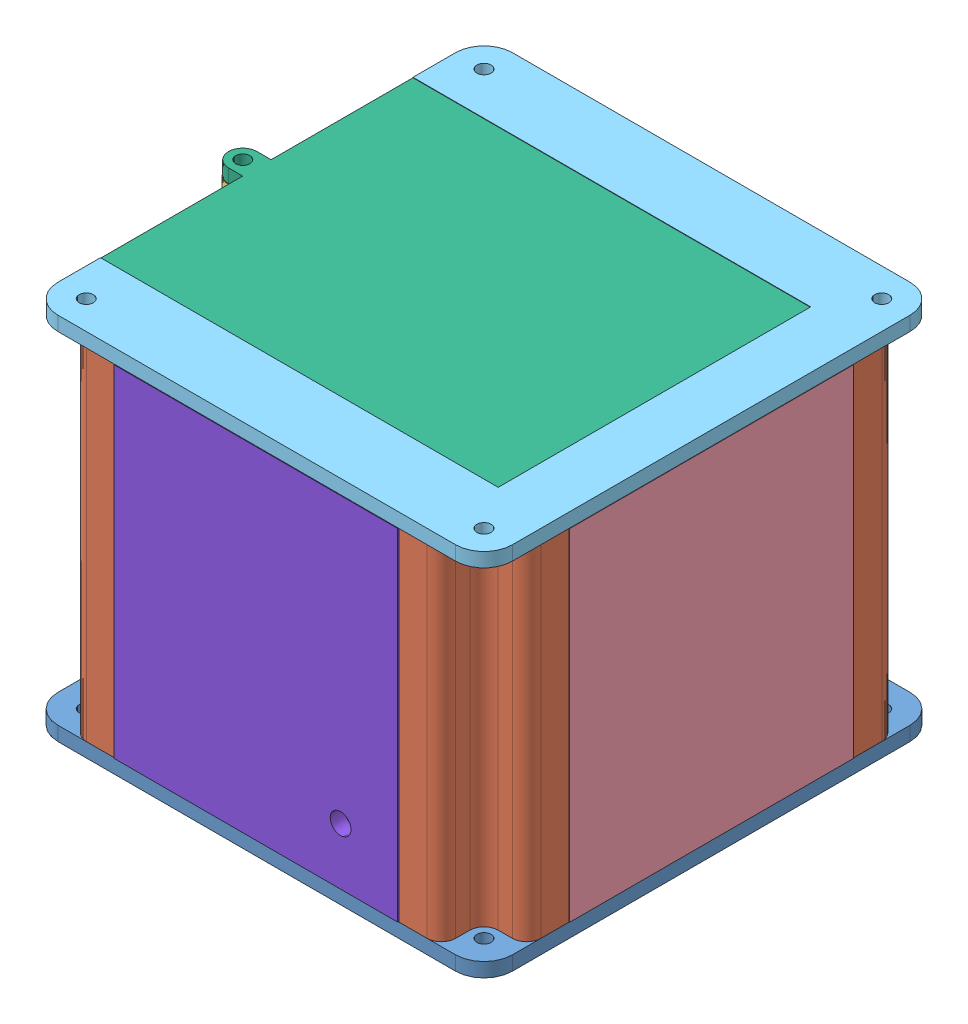
SolidWorks assembly Assem2, configuration Default. Lengths in mm.
Overall size (216.1 165.1 203.8).
11 component instances, 8 part files, 29 mates.
Components (placement in the parent):
- Base-1: Base [Default] at (-22.8191 97.9791 259.3464) size (203.2 6.35 203.2)
- pylons-1: pylons [Default] at (15.2809 256.7291 221.2464) x (0 0 1) z (0 -1 0) size (38.1 38.1 155.57)
- pylons-2: pylons [Default] at (15.2809 256.7291 94.2464) x (-1 0 0) z (0 -1 0) size (38.1 38.1 155.57)
- pylons-3: pylons [Default] at (142.2602 256.7291 94.1693) x (0 0 -1) z (0 -1 0) size (38.1 38.1 155.57)
- pylons-4: pylons [Default] at (142.2809 256.7291 221.2464) x (1 0 0) z (0 -1 0) size (38.1 38.1 155.57)
- Frontwall-1: Frontwall [Default] at (-16.4691 104.3291 88.1961) x (0 0 1) z (0 -1 0) size (139.4 19.05 152.4)
- Realwall-2: Realwall [Default] at (174.2309 104.3291 227.5964) x (0 0 -1) z (0 -1 0) size (139.5 6.35 152.4)
- top-1: top [Default] at (-22.8191 256.7291 94.2464) size (203.2 19.05 203.2)
- lid-1: lid [Default] at (154.7809 262.8791 87.8964) x (0 0 1) z (1 0 0) size (139.5 6.35 190.3)
- DiscAntennawall-1: DiscAntennawall [Default] at (8.9309 256.7291 62.1966) x (1 0 0) z (0 1 0) size (139.4 6.35 152.4)
- antennaholewall-1: antennaholewall [Default] at (8.9309 104.3291 253.2961) x (1 0 0) z (0 -1 0) size (139.4 6.35 152.4)
Mates (geometry in assembly coordinates):
- Coincident1: coincident: plane of Base-1 through (-22.8191 104.3291 259.3464) normal (0 1 0); plane of pylons-3 through (142.2602 104.3291 94.1693) normal (0 -1 0)
- Coincident2: coincident: plane of Base-1 through (158.8351 101.1541 77.6921) normal (-0.258819 0 0.965926); plane of pylons-3 through (149.233 101.1541 75.1193) normal (0.258819 0 -0.965926)
- Coincident3: coincident: plane of Base-1 through (149.233 101.1541 75.1193) normal (0.707107 0 0.707107); plane of pylons-3 through (142.2602 101.1541 82.0921) normal (-0.707107 0 -0.707107)
- Coincident4: coincident: plane of Base-1 through (-22.8191 104.3291 56.1464) normal (0 0 -1); plane of pylons-2 through (15.2809 104.3291 56.1464) normal (0 0 -1)
- Coincident5: coincident: plane of Base-1 through (-22.8191 104.3291 259.3464) normal (-1 0 0); plane of pylons-2 through (-22.8191 104.3291 75.1964) normal (-1 0 0)
- Coincident6: coincident: plane of Base-1 through (-22.8191 104.3291 259.3464) normal (0 1 0); plane of pylons-2 through (15.2809 104.3291 94.2464) normal (0 -1 0)
- Coincident7: coincident: plane of Base-1 through (-22.8191 104.3291 259.3464) normal (-1 0 0); plane of pylons-1 through (-22.8191 104.3291 221.2464) normal (-1 0 0)
- Coincident8: coincident: plane of Base-1 through (-22.8191 104.3291 259.3464) normal (0 0 1); plane of pylons-1 through (-3.7691 104.3291 259.3464) normal (0 0 1)
- Coincident9: coincident: plane of Base-1 through (-22.8191 104.3291 259.3464) normal (0 1 0); plane of pylons-1 through (15.2809 104.3291 221.2464) normal (0 -1 0)
- Coincident10: coincident: plane of Base-1 through (-22.8191 104.3291 259.3464) normal (0 0 1); plane of pylons-4 through (142.2809 104.3291 259.3464) normal (0 0 1)
- Coincident11: coincident: plane of Base-1 through (180.3809 104.3291 259.3464) normal (1 0 0); plane of pylons-4 through (180.3809 104.3291 240.2964) normal (1 0 0)
- Coincident12: coincident: plane of Base-1 through (-22.8191 104.3291 259.3464) normal (0 1 0); plane of pylons-4 through (142.2809 104.3291 221.2464) normal (0 -1 0)
- Coincident13: coincident: plane of pylons-1 through (-19.6441 256.7291 227.5964) normal (0 0 -1); plane of Frontwall-1 through (-22.8191 104.3291 227.5964) normal (0 0 1)
- Coincident14: coincident: plane of pylons-1 through (-16.4691 256.7291 221.2464) normal (-1 0 0); plane of Frontwall-1 through (-16.4691 104.3291 88.1961) normal (1 0 0)
- Coincident15: coincident: plane of Base-1 through (-22.8191 104.3291 259.3464) normal (0 1 0); plane of Frontwall-1 through (-22.8191 104.3291 88.1961) normal (0 -1 0)
- Coincident19: coincident: plane of pylons-4 through (177.2059 256.7291 227.5964) normal (0 0 -1); plane of Realwall-2 through (180.5809 104.3291 227.5964) normal (0 0 1)
- Coincident20: coincident: plane of pylons-4 through (177.2059 256.7291 221.2464) normal (-1 0 0); plane of Realwall-2 through (177.2059 104.3291 227.5964) normal (1 0 0)
- Coincident21: coincident: plane of Base-1 through (-22.8191 104.3291 259.3464) normal (0 1 0); plane of Realwall-2 through (180.5809 104.3291 227.5964) normal (0 -1 0)
- Concentric6: concentric: cylinder of pylons-1 through (5.7559 256.7291 230.7714) axis (0 -1 0) radius 4.7625; cylinder of top-1 through (5.7559 244.0291 230.7714) axis (0 1 0) radius 4.6625
- Concentric7: concentric: cylinder of pylons-2 through (5.7559 256.7291 84.7214) axis (0 -1 0) radius 4.7625; cylinder of top-1 through (5.7559 244.0291 84.7214) axis (0 1 0) radius 4.6625
- Coincident26: coincident: plane of top-1 through (-22.8191 259.9041 94.2464) normal (0 1 0); plane of lid-1 through (154.7809 259.9041 87.8964) normal (0 -1 0)
- Coincident27: coincident: plane of top-1 through (154.9809 259.9041 87.8964) normal (0 0 1); plane of lid-1 through (154.7809 256.5291 87.8964) normal (0 0 -1)
- Coincident28: coincident: plane of Frontwall-1 through (-22.8191 104.3291 88.1961) normal (-1 0 0); plane of lid-1 through (-22.8191 256.5291 87.8964) normal (-1 0 0)
- Coincident29: coincident: plane of Base-1 through (-22.8191 104.3291 259.3464) normal (0 1 0); plane of antennaholewall-1 through (8.9309 104.3291 259.6461) normal (0 -1 0)
- Coincident30: coincident: plane of pylons-1 through (15.2809 256.7291 256.1714) normal (0 0 -1); plane of antennaholewall-1 through (8.9309 104.3291 256.1714) normal (0 0 1)
- Coincident31: coincident: plane of pylons-1 through (8.9309 256.7291 256.1714) normal (1 0 0); plane of antennaholewall-1 through (8.9309 104.3291 259.6461) normal (-1 0 0)
- Coincident32: coincident: plane of Base-1 through (-22.8191 104.3291 259.3464) normal (0 1 0); plane of DiscAntennawall-1 through (8.9309 104.3291 55.8466) normal (0 -1 0)
- Coincident33: coincident: plane of pylons-2 through (15.2809 256.7291 59.3214) normal (0 0 1); plane of DiscAntennawall-1 through (8.9309 256.7291 59.3214) normal (0 0 -1)
- Coincident34: coincident: plane of pylons-2 through (8.9309 256.7291 59.3214) normal (1 0 0); plane of DiscAntennawall-1 through (8.9309 256.7291 55.8466) normal (-1 0 0)
